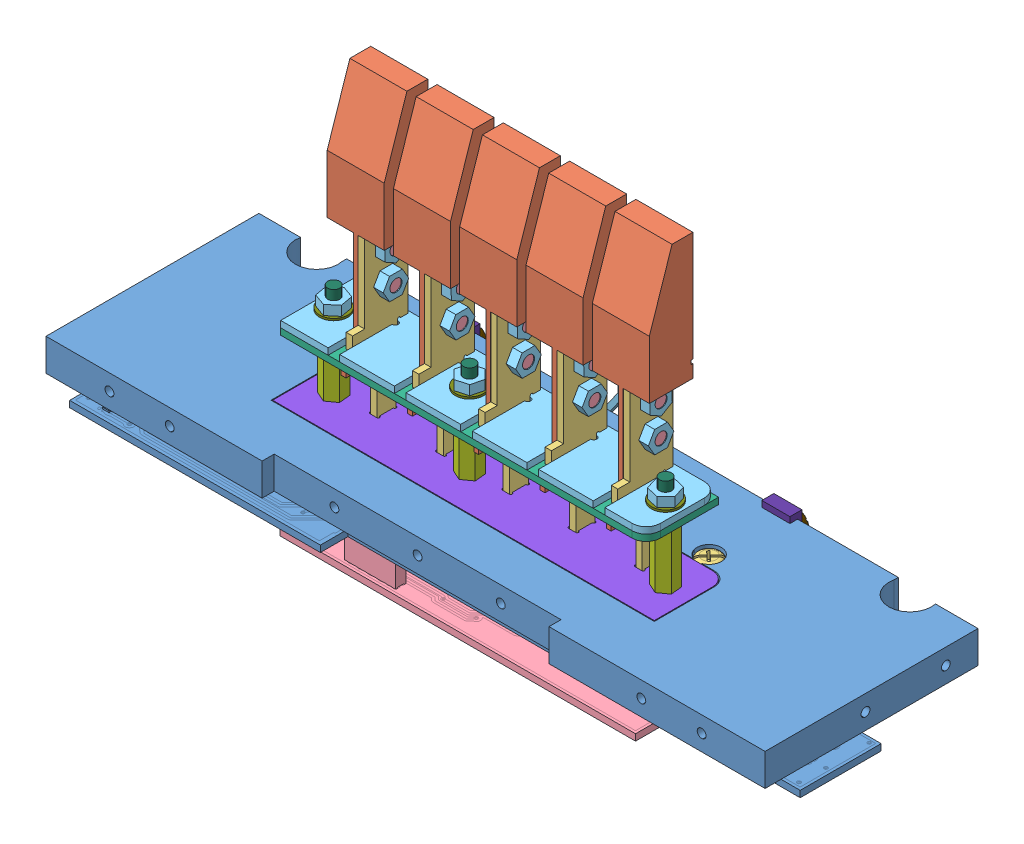
SolidWorks assembly 0200_ASM_Keyboard_PCB_stepmotor, configuration Default. Lengths in mm.
Overall size (179 155.71 164.54).
83 component instances, 24 part files, 108 mates.
Components (placement in the parent):
- 0201 Keyboard_PCB_holder-1: 0201 Keyboard_PCB_holder [Domyślna] at (-12.0126 94.407 53.9399) size (179 8 54.1)
- 0202 Button_ASM-1: 0202 Button_ASM [Domyślna] at (47.1081 156.1513 102.1514) x (0 1 0) z (1 0 0) size (82.15 13.85 14.2)
  - 0008 Button_Mustang_radio-1: 0008 Button_Mustang_radio [Domyślna] at (23.1329 -11.9839 53.65) size (60.75 13.85 14.2)
  - 0202_02 Button_pusher-1: 0202_02 Button_pusher [Domyślna] at (-73.7457 12.6375 84.3669) x (0 0 1) z (1 0 0) size (1.62 13.8 50.65)
  - 0301_03 M3_5 screw-1: 0301_03 M3_5 screw [Domyślna] at (-23.1095 5.1722 60.15) x (0.994507 -0.104669 0) z (0 0 -1) size (6 6 7.48)
  - 0301_03 M3_5 screw-2: 0301_03 M3_5 screw [Domyślna] at (-13.9404 2.6786 60.15) x (0.570039 -0.821618 0) z (0 0 -1) size (6 6 7.48)
  - 0301_02 M3 nut-1: 0301_02 M3 nut [Domyślna] at (-17.2457 2.6499 62.95) x (0.871112 -0.491084 0) z (0 0 1) size (5.51 6.35 2.4)
  - 0301_02 M3 nut-2: 0301_02 M3 nut [Domyślna] at (-25.2457 2.6499 62.95) size (5.51 6.35 2.4)
- 0202 Button_ASM-10: 0202 Button_ASM [Domyślna] at (63.6081 156.1513 102.1514) x (0 1 0) z (1 0 0) size (82.15 13.85 14.2)
  - 0008 Button_Mustang_radio-1: 0008 Button_Mustang_radio [Domyślna] at (23.1329 -11.9839 53.65) size (60.75 13.85 14.2)
  - 0202_02 Button_pusher-1: 0202_02 Button_pusher [Domyślna] at (-73.7457 12.6375 84.3669) x (0 0 1) z (1 0 0) size (1.62 13.8 50.65)
  - 0301_03 M3_5 screw-1: 0301_03 M3_5 screw [Domyślna] at (-23.1095 5.1722 60.15) x (0.994507 -0.104669 0) z (0 0 -1) size (6 6 7.48)
  - 0301_03 M3_5 screw-2: 0301_03 M3_5 screw [Domyślna] at (-13.9404 2.6786 60.15) x (0.570039 -0.821618 0) z (0 0 -1) size (6 6 7.48)
  - 0301_02 M3 nut-1: 0301_02 M3 nut [Domyślna] at (-17.2457 2.6499 62.95) x (0.871112 -0.491084 0) z (0 0 1) size (5.51 6.35 2.4)
  - 0301_02 M3 nut-2: 0301_02 M3 nut [Domyślna] at (-25.2457 2.6499 62.95) size (5.51 6.35 2.4)
- 0202 Button_ASM-11: 0202 Button_ASM [Domyślna] at (80.1081 156.1513 102.1514) x (0 1 0) z (1 0 0) size (82.15 13.85 14.2)
  - 0008 Button_Mustang_radio-1: 0008 Button_Mustang_radio [Domyślna] at (23.1329 -11.9839 53.65) size (60.75 13.85 14.2)
  - 0202_02 Button_pusher-1: 0202_02 Button_pusher [Domyślna] at (-73.7457 12.6375 84.3669) x (0 0 1) z (1 0 0) size (1.62 13.8 50.65)
  - 0301_03 M3_5 screw-1: 0301_03 M3_5 screw [Domyślna] at (-23.1095 5.1722 60.15) x (0.994507 -0.104669 0) z (0 0 -1) size (6 6 7.48)
  - 0301_03 M3_5 screw-2: 0301_03 M3_5 screw [Domyślna] at (-13.9404 2.6786 60.15) x (0.570039 -0.821618 0) z (0 0 -1) size (6 6 7.48)
  - 0301_02 M3 nut-1: 0301_02 M3 nut [Domyślna] at (-17.2457 2.6499 62.95) x (0.871112 -0.491084 0) z (0 0 1) size (5.51 6.35 2.4)
  - 0301_02 M3 nut-2: 0301_02 M3 nut [Domyślna] at (-25.2457 2.6499 62.95) size (5.51 6.35 2.4)
- 0202 Button_ASM-12: 0202 Button_ASM [Domyślna] at (30.6081 156.1513 102.1514) x (0 1 0) z (1 0 0) size (82.15 13.85 14.2)
  - 0008 Button_Mustang_radio-1: 0008 Button_Mustang_radio [Domyślna] at (23.1329 -11.9839 53.65) size (60.75 13.85 14.2)
  - 0202_02 Button_pusher-1: 0202_02 Button_pusher [Domyślna] at (-73.7457 12.6375 84.3669) x (0 0 1) z (1 0 0) size (1.62 13.8 50.65)
  - 0301_03 M3_5 screw-1: 0301_03 M3_5 screw [Domyślna] at (-23.1095 5.1722 60.15) x (0.994507 -0.104669 0) z (0 0 -1) size (6 6 7.48)
  - 0301_03 M3_5 screw-2: 0301_03 M3_5 screw [Domyślna] at (-13.9404 2.6786 60.15) x (0.570039 -0.821618 0) z (0 0 -1) size (6 6 7.48)
  - 0301_02 M3 nut-1: 0301_02 M3 nut [Domyślna] at (-17.2457 2.6499 62.95) x (0.871112 -0.491084 0) z (0 0 1) size (5.51 6.35 2.4)
  - 0301_02 M3 nut-2: 0301_02 M3 nut [Domyślna] at (-25.2457 2.6499 62.95) size (5.51 6.35 2.4)
- 0202 Button_ASM-13: 0202 Button_ASM [Domyślna] at (14.1081 156.1513 102.1514) x (0 1 0) z (1 0 0) size (82.15 13.85 14.2)
  - 0008 Button_Mustang_radio-1: 0008 Button_Mustang_radio [Domyślna] at (23.1329 -11.9839 53.65) size (60.75 13.85 14.2)
  - 0202_02 Button_pusher-1: 0202_02 Button_pusher [Domyślna] at (-73.7457 12.6375 84.3669) x (0 0 1) z (1 0 0) size (1.62 13.8 50.65)
  - 0301_03 M3_5 screw-1: 0301_03 M3_5 screw [Domyślna] at (-23.1095 5.1722 60.15) x (0.994507 -0.104669 0) z (0 0 -1) size (6 6 7.48)
  - 0301_03 M3_5 screw-2: 0301_03 M3_5 screw [Domyślna] at (-13.9404 2.6786 60.15) x (0.570039 -0.821618 0) z (0 0 -1) size (6 6 7.48)
  - 0301_02 M3 nut-1: 0301_02 M3 nut [Domyślna] at (-17.2457 2.6499 62.95) x (0.871112 -0.491084 0) z (0 0 1) size (5.51 6.35 2.4)
  - 0301_02 M3 nut-2: 0301_02 M3 nut [Domyślna] at (-25.2457 2.6499 62.95) size (5.51 6.35 2.4)
- 0203_02 Popychacz_plytka_przod_tyl-1: 0203_02 Popychacz_plytka_przod_tyl [Domyślna] at (92.8637 117.407 124.3828) x (1 0 0) z (0 1 0) size (91 18 1.6)
- 0302_01_15 AVT_M3_15 W_W-1: 0302_01_15 AVT_M3_15 W_W [Domyślna] at (66.5581 117.407 107.4012) x (1 0 0) z (0 -1 0) size (5.25 5.75 15)
- 0302_01_15 AVT_M3_15 W_W-2: 0302_01_15 AVT_M3_15 W_W [Domyślna] at (149.1581 117.407 107.4012) x (1 0 0) z (0 -1 0) size (5.25 5.75 15)
- 0204_01_02 Popychacz_plytka_tyl_obie-3: 0204_01_02 Popychacz_plytka_tyl_obie [Domyślna] at (109.6559 100.807 132.332) x (1 0 0) z (0 1 0) size (95 164.54 1.61)
- 0204_01_02 Popychacz_plytka_tyl_obie-5: 0204_01_02 Popychacz_plytka_tyl_obie [Domyślna] at (109.6559 94.407 132.332) x (1 0 0) z (0 1 0) size (95 164.54 1.61)
- 0303_01_20 AVT_ FIX-3.5-7-1: 0303_01_20 AVT_ FIX-3.5-7 [Domyślna] at (149.1581 94.407 107.4012) x (-0.241888 0 -0.970304) z (0 -1 0) size (6.3 6.3 7)
- 0303_01_20 AVT_ FIX-3.5-7-2: 0303_01_20 AVT_ FIX-3.5-7 [Domyślna] at (66.5581 94.407 107.4012) x (0.447853 0 0.894107) z (0 -1 0) size (6.3 6.3 7)
- 0204 18_degree_Stepper_motor_ASM-1: 0204 18_degree_Stepper_motor_ASM [Domyślna] at (84.148 89.7518 -20.7788) x (-1 0 0) z (0 0 1) size (123.94 152.42 25.76)
  - Podstawa-1: Podstawa [Domyślna] at (-23.4331 3.418 97.5) size (123.94 152.42 15.11)
  - PCB_złożenie_PART_ASM-1: PCB_złożenie_PART_ASM [Domyślna] at (30.2257 4.23 104.2) x (1 0 0) z (0 0 -1) size (19.02 7.5 10.76)
  - prowadnica-1: prowadnica [Domyślna] at (21.2899 4.3448 105) x (0 0 1) z (-1 0 0) size (3 3 90)
  - suwak-1: suwak [Domyślna] at (-12.9526 -22.7417 105.613) x (0 -1 0) z (-1 0 0) size (12.4 15 7.5)
  - prowadnica-2: prowadnica [Domyślna] at (-68.7101 0.0448 109.845) x (0 0 -1) z (1 0 0) size (3 3 90)
  - prowadnica-3: prowadnica [Domyślna] at (21.2899 0.0448 100.155) x (0 0 1) z (-1 0 0) size (3 3 90)
- 0004 HMI pointer-1: 0004 HMI pointer [Default] at (105.5919 80.157 79.2046) x (0 -1 0) z (0 0 1) size (54.01 6.75 30.62)
- 0301_05 M3_40 screw-1: 0301_05 M3_40 screw [Domyślna] at (151.1235 85.907 110.0589) x (-0.3299 0 0.944016) z (0 -1 0) size (6 6 42.48)
- 0301_01 M3 washer-2: 0301_01 M3 washer [Domyślna] at (149.1581 120.607 107.4012) size (7 0.5 7)
- 0301_02 M3 nut-2: 0301_02 M3 nut [Domyślna] at (149.1581 123.507 107.4012) x (0.957402 0 -0.288759) z (0 -1 0) size (5.51 6.35 2.4)
- 0301_01 M3 washer-3: 0301_01 M3 washer [Domyślna] at (66.5581 120.607 107.4012) size (7 0.5 7)
- 0301_02 M3 nut-3: 0301_02 M3 nut [Domyślna] at (66.5581 121.107 107.4012) x (0.343062 0 -0.939313) z (0 1 0) size (5.51 6.35 2.4)
- 0301_05 M3_40 screw-2: 0301_05 M3_40 screw [Domyślna] at (69.5558 85.907 108.794) x (0.162196 0 0.986759) z (0 -1 0) size (6 6 42.48)
- 0303_01_20 AVT_ FIX-3.5-7-3: 0303_01_20 AVT_ FIX-3.5-7 [Domyślna] at (100.3581 94.407 107.4012) x (-0.431925 0 0.90191) z (0 -1 0) size (6.3 6.3 7)
- 0301_05 M3_40 screw-3: 0301_05 M3_40 screw [Domyślna] at (103.5204 85.907 106.4392) x (0.779048 0 0.626964) z (0 -1 0) size (6 6 42.48)
- 0301_01 M3 washer-4: 0301_01 M3 washer [Domyślna] at (100.3581 120.607 107.4012) size (7 0.5 7)
- 0301_02 M3 nut-4: 0301_02 M3 nut [Domyślna] at (100.3581 123.507 107.4012) x (0.694406 0 -0.719583) z (0 -1 0) size (5.51 6.35 2.4)
- 0302_01_15 AVT_M3_15 W_W-3: 0302_01_15 AVT_M3_15 W_W [Domyślna] at (100.3581 117.407 107.4012) x (1 0 0) z (0 -1 0) size (5.25 5.75 15)
- 0202 Motor holder-METAL-2: 0202 Motor holder-METAL [Domyślna] at (146.9154 94.407 82.6208) x (0 0 1) z (0 1 0) size (22.72 7 9) (hidden)
- 0202 Motor holder-METAL-3: 0202 Motor holder-METAL [Domyślna] at (66.7554 94.407 82.6208) x (0 0 1) z (0 1 0) size (22.72 7 9) (hidden)
- 0202 Motor holder-PRINTED-1: 0202 Motor holder-PRINTED [Domyślna] at (66.7554 93.407 82.9279) x (0 0 1) z (0 1 0) size (23 7 10.6)
- 0202 Motor holder-PRINTED-2: 0202 Motor holder-PRINTED [Domyślna] at (146.9154 93.407 82.9279) x (0 0 1) z (0 1 0) size (23 7 10.6)
- 0301_02 M3 nut-5: 0301_02 M3 nut [Domyślna] at (147.9381 91.007 95.3212) x (1 0 0) z (0 1 0) size (5.51 6.35 2.4)
- 0301_02 M3 nut-6: 0301_02 M3 nut [Domyślna] at (67.7781 93.407 95.3212) x (0.884436 0 0.466662) z (0 -1 0) size (5.51 6.35 2.4)
- 0301_01 M3 washer-7: 0301_01 M3 washer [Domyślna] at (147.9381 98.407 75.7212) x (1 0 0) z (0 1 0) size (7 0.5 7)
- 0301_03 M3_10 screw-1: 0301_03 M3_10 screw [Domyślna] at (150.929 96.9997 75.2212) x (0.157411 -0.987533 0) z (0 0 -1) size (6 6 12.48)
- 0301_01 M3 washer-8: 0301_01 M3 washer [Domyślna] at (67.7781 98.407 75.7212) x (1 0 0) z (0 1 0) size (7 0.5 7)
- 0301_03 M3_10 screw-2: 0301_03 M3_10 screw [Domyślna] at (71.0607 98.795 75.2212) x (0.656002 -0.754759 0) z (0 0 -1) size (6 6 12.48)
- 04_Keyboard-1: 04_Keyboard [Domyślna] at (-38.7519 87.537 14.8212) x (1 0 0) z (0 1 0) size (175 31 14.44)
- 0303_01_20 AVT_ FIX-3.5-14-3: 0303_01_20 AVT_ FIX-3.5-14 [Domyślna] at (147.9381 77.007 95.3212) x (1 0 0) z (0 1 0) size (6.3 6.3 14)
- 0303_01_20 AVT_ FIX-3.5-14-4: 0303_01_20 AVT_ FIX-3.5-14 [Domyślna] at (67.7781 77.007 95.3212) x (0.987736 0 -0.156132) z (0 1 0) size (6.3 6.3 14)
- 0301_04 M3_30 screw-1: 0301_04 M3_30 screw [Domyślna] at (149.0646 99.807 98.4288) x (0.968896 0 0.24747) z (0 1 0) size (6 6 32.48)
- 0301_04 M3_30 screw-2: 0301_04 M3_30 screw [Domyślna] at (70.0661 99.807 92.9357) x (-0.206921 0 -0.978358) z (0 1 0) size (6 6 32.48)
- 0301_01 M3 washer-9: 0301_01 M3 washer [Domyślna] at (147.9381 74.877 95.3212) size (7 0.5 7)
- 0301_02 M3 nut-7: 0301_02 M3 nut [Domyślna] at (147.9381 72.477 95.3212) x (1 0 0) z (0 1 0) size (5.51 6.35 2.4)
- 0301_02 M3 nut-8: 0301_02 M3 nut [Domyślna] at (67.7781 72.477 95.3212) x (1 0 0) z (0 1 0) size (5.51 6.35 2.4)
- 0301_01 M3 washer-10: 0301_01 M3 washer [Domyślna] at (67.7781 74.877 95.3212) size (7 0.5 7)
- 05_01 HMI_driver_stepper_motor-1: 05_01 HMI_driver_stepper_motor [Domyślna] at (-38.7719 76.977 14.8412) x (1 0 0) z (0 1 0) size (88.53 43.87 18.6)
- 0203_01 Popychacz_plytka_przod_przod-2: 0203_01 Popychacz_plytka_przod_przod [Domyślna] at (92.8637 119.007 124.3828) x (1 0 0) z (0 1 0) size (106.59 18 1.6)
Mates (geometry in assembly coordinates):
- Równolegle1: parallel aligned: plane of 0202 Button_ASM-1/0008 Button_Mustang_radio-1 through (107.8581 179.2842 90.1675) normal (1 0 0); plane of assembly through (107.8581 0 0) normal (1 0 0)
- Równolegle2: parallel anti-aligned: plane of 0201 Keyboard_PCB_holder-1 through (-12.0126 102.407 53.9399) normal (0 1 0); plane of 0202 Button_ASM-1/0202_02 Button_pusher-1 through (100.7581 113.1555 90.1675) normal (0 -1 0)
- Wspólnie2: coincident aligned: plane of 0202 Button_ASM-1/0008 Button_Mustang_radio-1 through (107.8581 179.2842 90.1675) normal (1 0 0); plane of assembly through (107.8581 0 0) normal (1 0 0)
- Wspólnie3: coincident aligned: plane of 0202 Button_ASM-1/0008 Button_Mustang_radio-1 through (114.9581 142.4055 99.3812) normal (0 0 -1); plane of assembly through (0 0 99.3812) normal (0 0 -1)
- Odległość1: distance = 1 mm aligned: plane of 0203_02 Popychacz_plytka_przod_tyl-1 through (62.3581 119.007 98.4012) normal (0 0 -1); plane of 0202 Button_ASM-10/0202_02 Button_pusher-1 through (124.9581 142.4055 99.4012) normal (0 0 -1)
- Wspólnie7: coincident aligned: plane of 0203_02 Popychacz_plytka_przod_tyl-1 through (107.8581 117.407 124.3828) normal (1 0 0); plane of assembly through (107.8581 0 0) normal (1 0 0)
- Wspólnie8: coincident anti-aligned: plane of 0202 Button_ASM-13/0008 Button_Mustang_radio-1 through (75.4581 117.407 113.2312) normal (0 1 0); plane of 0203_02 Popychacz_plytka_przod_tyl-1 through (92.8637 117.407 124.3828) normal (0 -1 0)
- Odległość2: distance = 15 mm anti-aligned: plane of 0201 Keyboard_PCB_holder-1 through (-12.0126 102.407 53.9399) normal (0 1 0); plane of 0203_02 Popychacz_plytka_przod_tyl-1 through (92.8637 117.407 124.3828) normal (0 -1 0)
- Wspólnie14: coincident anti-aligned: plane of 0203_02 Popychacz_plytka_przod_tyl-1 through (92.8637 117.407 124.3828) normal (0 -1 0); plane of 0302_01_15 AVT_M3_15 W_W-1 through (66.5581 117.407 107.4012) normal (0 1 0)
- Wspólnie15: coincident anti-aligned: plane of 0203_02 Popychacz_plytka_przod_tyl-1 through (92.8637 117.407 124.3828) normal (0 -1 0); plane of 0302_01_15 AVT_M3_15 W_W-2 through (149.1581 117.407 107.4012) normal (0 1 0)
- Równolegle5: parallel anti-aligned: plane of 0201 Keyboard_PCB_holder-1 through (-12.0126 102.407 53.9399) normal (0 1 0); plane of 0204_01_02 Popychacz_plytka_tyl_obie-3 through (109.6559 100.807 132.332) normal (0 -1 0)
- Wspólnie22: coincident aligned: plane of 0201 Keyboard_PCB_holder-1 through (-12.0126 102.407 53.9399) normal (0 1 0); plane of 0204_01_02 Popychacz_plytka_tyl_obie-3 through (109.6559 102.407 132.332) normal (0 1 0)
- Równolegle7: parallel anti-aligned: plane of 0201 Keyboard_PCB_holder-1 through (-12.0126 102.407 53.9399) normal (0 1 0); plane of 0204_01_02 Popychacz_plytka_tyl_obie-5 through (109.6559 94.407 132.332) normal (0 -1 0)
- Wspólnie27: coincident aligned: plane of 0204_01_02 Popychacz_plytka_tyl_obie-3 through (107.8581 100.807 132.332) normal (1 0 0); plane of 0204_01_02 Popychacz_plytka_tyl_obie-5 through (107.8581 94.407 132.332) normal (1 0 0)
- Wspólnie28: coincident aligned: plane of 0204_01_02 Popychacz_plytka_tyl_obie-3 through (109.6559 100.807 107.4012) normal (0 0 -1); plane of 0204_01_02 Popychacz_plytka_tyl_obie-5 through (109.6559 94.407 107.4012) normal (0 0 -1)
- Wspólnie29: coincident aligned: plane of 0201 Keyboard_PCB_holder-1 through (-12.0126 94.407 53.9399) normal (0 -1 0); plane of 0204_01_02 Popychacz_plytka_tyl_obie-5 through (109.6559 94.407 132.332) normal (0 -1 0)
- Koncentryczne2: concentric anti-aligned: circle of 0204_01_02 Popychacz_plytka_tyl_obie-5; cylinder of 0303_01_20 AVT_ FIX-3.5-7-1 through (149.1581 87.407 107.4012) axis (0 1 0) radius 1.75
- Wspólnie30: coincident anti-aligned: plane of 0204_01_02 Popychacz_plytka_tyl_obie-5 through (109.6559 94.407 132.332) normal (0 -1 0); plane of 0303_01_20 AVT_ FIX-3.5-7-1 through (149.1581 94.407 107.4012) normal (0 1 0)
- Koncentryczne3: concentric anti-aligned: cylinder of 0204_01_02 Popychacz_plytka_tyl_obie-5 through (66.5581 90.1644 107.4012) axis (0 1 0) radius 1.5; circle of 0303_01_20 AVT_ FIX-3.5-7-2
- Wspólnie31: coincident aligned: plane of 0204_01_02 Popychacz_plytka_tyl_obie-5 through (109.6559 94.407 132.332) normal (0 -1 0); circle of 0303_01_20 AVT_ FIX-3.5-7-2
- Wspólnie34: coincident aligned: plane of 0201 Keyboard_PCB_holder-1 through (-12.0126 94.407 76.7212) normal (0 0 -1); plane of 0204 18_degree_Stepper_motor_ASM-1/Podstawa-1 through (153.3581 94.907 76.7212) normal (0 0 -1)
- Równolegle9: parallel anti-aligned: plane of 0201 Keyboard_PCB_holder-1 through (-12.0126 94.407 53.9399) normal (0 -1 0); plane of 0204 18_degree_Stepper_motor_ASM-1/Podstawa-1 through (153.3581 95.907 91.7212) normal (0 1 0)
- Wspólnie35: coincident aligned: plane of 0204_01_02 Popychacz_plytka_tyl_obie-5 through (107.8581 94.407 132.332) normal (1 0 0); plane of 0204 18_degree_Stepper_motor_ASM-1/Podstawa-1 through (107.8581 86.3338 76.7212) normal (1 0 0)
- Wspólnie36: coincident aligned: plane of 0201 Keyboard_PCB_holder-1 through (-12.0126 94.407 53.9399) normal (0 -1 0); plane of 0204 18_degree_Stepper_motor_ASM-1/Podstawa-1 through (151.8581 94.407 91.7212) normal (0 -1 0)
- Wspólnie37: coincident anti-aligned: plane of 0204 18_degree_Stepper_motor_ASM-1/suwak-1 through (104.6006 80.907 91.7212) normal (0 -1 0); plane of 0004 HMI pointer-1 through (105.5919 80.907 79.2046) normal (0 1 0)
- Wspólnie38: coincident anti-aligned: plane of 0204 18_degree_Stepper_motor_ASM-1/suwak-1 through (104.6006 80.907 76.7212) normal (0 0 -1); plane of 0004 HMI pointer-1 through (105.5919 80.157 76.7212) normal (0 0 1)
- Wspólnie39: coincident aligned: plane of 0204 18_degree_Stepper_motor_ASM-1/suwak-1 through (104.6006 112.4935 84.8342) normal (1 0 0); plane of 0004 HMI pointer-1 through (104.6006 80.907 75.9712) normal (1 0 0)
- Koncentryczne5: concentric aligned: circle of 0303_01_20 AVT_ FIX-3.5-7-1; cylinder of 0301_05 M3_40 screw-1 through (149.1581 125.907 107.4012) axis (0 -1 0) radius 1.5
- Odległość3: distance = 1.5 mm anti-aligned: plane of 0303_01_20 AVT_ FIX-3.5-7-1 through (149.1581 87.407 107.4012) normal (0 -1 0); plane of 0301_05 M3_40 screw-1 through (149.1581 85.907 107.4012) normal (0 1 0)
- Koncentryczne6: concentric anti-aligned: cylinder of 0301_05 M3_40 screw-1 through (149.1581 125.907 107.4012) axis (0 -1 0) radius 1.5; circle of 0301_01 M3 washer-2
- Koncentryczne7: concentric anti-aligned: cylinder of 0301_05 M3_40 screw-1 through (149.1581 125.907 107.4012) axis (0 -1 0) radius 1.5; cylinder of 0301_02 M3 nut-2 through (149.1581 121.107 107.4012) axis (0 1 0) radius 1.4964
- Wspólnie46: coincident anti-aligned: plane of 0301_01 M3 washer-2 through (149.1581 121.107 107.4012) normal (0 1 0); plane of 0301_02 M3 nut-2 through (149.1581 121.107 107.4012) normal (0 -1 0)
- Koncentryczne8: concentric anti-aligned: cylinder of 0303_01_20 AVT_ FIX-3.5-7-2 through (66.5581 87.407 107.4012) axis (0 1 0) radius 1.75; cylinder of 0301_05 M3_40 screw-2 through (66.5581 125.907 107.4012) axis (0 -1 0) radius 1.5
- Odległość4: distance = 1.5 mm anti-aligned: plane of 0303_01_20 AVT_ FIX-3.5-7-2 through (66.5581 87.407 107.4012) normal (0 -1 0); plane of 0301_05 M3_40 screw-2 through (66.5581 85.907 107.4012) normal (0 1 0)
- Koncentryczne9: concentric anti-aligned: circle of 0301_01 M3 washer-3; cylinder of 0301_05 M3_40 screw-2 through (66.5581 125.907 107.4012) axis (0 -1 0) radius 1.5
- Koncentryczne10: concentric anti-aligned: circle of 0301_02 M3 nut-3; cylinder of 0301_05 M3_40 screw-2 through (66.5581 125.907 107.4012) axis (0 -1 0) radius 1.5
- Wspólnie49: coincident anti-aligned: circle of 0301_01 M3 washer-3; plane of 0301_02 M3 nut-3 through (66.5581 121.107 107.4012) normal (0 -1 0)
- Koncentryczne12: concentric anti-aligned: circle of 0204_01_02 Popychacz_plytka_tyl_obie-5; cylinder of 0303_01_20 AVT_ FIX-3.5-7-3 through (100.3581 87.407 107.4012) axis (0 1 0) radius 1.75
- Wspólnie50: coincident anti-aligned: plane of 0204_01_02 Popychacz_plytka_tyl_obie-5 through (109.6559 94.407 132.332) normal (0 -1 0); plane of 0303_01_20 AVT_ FIX-3.5-7-3 through (100.3581 94.407 107.4012) normal (0 1 0)
- Koncentryczne14: concentric anti-aligned: cylinder of 0303_01_20 AVT_ FIX-3.5-7-3 through (100.3581 87.407 107.4012) axis (0 1 0) radius 1.75; cylinder of 0301_05 M3_40 screw-3 through (100.3581 125.907 107.4012) axis (0 -1 0) radius 1.5
- Odległość6: distance = 1.5 mm anti-aligned: plane of 0303_01_20 AVT_ FIX-3.5-7-3 through (100.3581 87.407 107.4012) normal (0 -1 0); plane of 0301_05 M3_40 screw-3 through (100.3581 85.907 107.4012) normal (0 1 0)
- Koncentryczne15: concentric aligned: cylinder of 0301_05 M3_40 screw-3 through (100.3581 125.907 107.4012) axis (0 -1 0) radius 1.5; cylinder of 0301_01 M3 washer-4 through (100.3581 121.107 107.4012) axis (0 -1 0) radius 1.6
- Koncentryczne16: concentric anti-aligned: cylinder of 0301_05 M3_40 screw-3 through (100.3581 125.907 107.4012) axis (0 -1 0) radius 1.5; cylinder of 0301_02 M3 nut-4 through (100.3581 121.107 107.4012) axis (0 1 0) radius 1.4964
- Wspólnie54: coincident anti-aligned: plane of 0301_01 M3 washer-4 through (100.3581 121.107 107.4012) normal (0 1 0); plane of 0301_02 M3 nut-4 through (100.3581 121.107 107.4012) normal (0 -1 0)
- Koncentryczne17: concentric anti-aligned: cylinder of 0301_05 M3_40 screw-3 through (100.3581 125.907 107.4012) axis (0 -1 0) radius 1.5; cylinder of 0302_01_15 AVT_M3_15 W_W-3 through (100.3581 102.407 107.4012) axis (0 1 0) radius 1.5
- Wspólnie55: coincident anti-aligned: plane of 0204_01_02 Popychacz_plytka_tyl_obie-3 through (109.6559 102.407 132.332) normal (0 1 0); plane of 0302_01_15 AVT_M3_15 W_W-3 through (100.3581 102.407 107.4012) normal (0 -1 0)
- Wspólnie56: coincident anti-aligned: plane of 0201 Keyboard_PCB_holder-1 through (-12.0126 94.407 53.9399) normal (0 -1 0); plane of 0202 Motor holder-METAL-2 through (147.9381 94.407 95.3212) normal (0 1 0)
- Równolegle10: parallel aligned: plane of 0204 18_degree_Stepper_motor_ASM-1/Podstawa-1 through (154.3581 80.907 91.7212) normal (1 0 0); plane of 0202 Motor holder-METAL-2 through (151.4381 93.407 98.4367) normal (1 0 0)
- Wspólnie59: coincident anti-aligned: plane of 0201 Keyboard_PCB_holder-1 through (-12.0126 94.407 53.9399) normal (0 -1 0); plane of 0202 Motor holder-METAL-3 through (67.7781 94.407 95.3212) normal (0 1 0)
- Równolegle11: parallel aligned: plane of 0204 18_degree_Stepper_motor_ASM-1/Podstawa-1 through (152.8581 80.907 91.7212) normal (-1 0 0); plane of 0202 Motor holder-METAL-3 through (64.2781 93.407 76.7212) normal (-1 0 0)
- Wspólnie66: coincident anti-aligned: plane of 0202 Motor holder-METAL-2 through (146.9154 94.407 75.7212) normal (0 0 -1); plane of 0301_01 M3 washer-7 through (147.9381 98.407 75.7212) normal (0 0 1)
- Wspólnie67: coincident aligned: cylinder of 0202 Motor holder-METAL-2 through (147.9381 98.407 83.171) axis (0 0 -1) radius 1.6; circle of 0301_01 M3 washer-7
- Wspólnie68: coincident anti-aligned: plane of 0301_01 M3 washer-7 through (147.9381 98.407 75.2212) normal (0 0 -1); plane of 0301_03 M3_10 screw-1 through (147.9381 98.407 75.2212) normal (0 0 1)
- Koncentryczne28: concentric aligned: circle of 0301_01 M3 washer-7; cylinder of 0301_03 M3_10 screw-1 through (147.9381 98.407 85.2212) axis (0 0 -1) radius 1.5
- Wspólnie69: coincident anti-aligned: plane of 0202 Motor holder-METAL-3 through (66.7554 94.407 75.7212) normal (0 0 -1); plane of 0301_01 M3 washer-8 through (67.7781 98.407 75.7212) normal (0 0 1)
- Wspólnie71: coincident aligned: circle of 0202 Motor holder-METAL-3; circle of 0301_01 M3 washer-8
- Wspólnie72: coincident anti-aligned: plane of 0301_01 M3 washer-8 through (67.7781 98.407 75.2212) normal (0 0 -1); plane of 0301_03 M3_10 screw-2 through (67.7781 98.407 75.2212) normal (0 0 1)
- Koncentryczne29: concentric aligned: circle of 0301_01 M3 washer-8; cylinder of 0301_03 M3_10 screw-2 through (67.7781 98.407 85.2212) axis (0 0 -1) radius 1.5
- Wspólnie77: coincident: plane of 0201 Keyboard_PCB_holder-1 through (-12.0126 94.407 76.7212) normal (0 0 -1); line of 0202 Motor holder-METAL-2 through (144.4381 94.907 76.7212) axis (0 1 0)
- Wspólnie78: coincident: plane of 0201 Keyboard_PCB_holder-1 through (-12.0126 94.407 76.7212) normal (0 0 -1); line of 0202 Motor holder-METAL-3 through (71.2781 102.407 76.7212) axis (0 -1 0)
- Koncentryczne35: concentric anti-aligned: cylinder of 0201 Keyboard_PCB_holder-1 through (147.9381 106.6496 95.3212) axis (0 -1 0) radius 1.5; cylinder of 0202 Motor holder-METAL-2 through (147.9381 93.407 95.3212) axis (0 1 0) radius 1.6
- Koncentryczne36: concentric anti-aligned: cylinder of 0201 Keyboard_PCB_holder-1 through (67.7781 106.6496 95.3212) axis (0 -1 0) radius 1.5; cylinder of 0202 Motor holder-METAL-3 through (67.7781 93.407 95.3212) axis (0 1 0) radius 1.6
- Koncentryczne44: concentric aligned: cylinder of 0201 Keyboard_PCB_holder-1 through (147.9381 106.6496 95.3212) axis (0 -1 0) radius 1.5; cylinder of 0301_02 M3 nut-5 through (147.9381 93.407 95.3212) axis (0 -1 0) radius 1.4964
- Wspólnie84: coincident anti-aligned: plane of 0202 Motor holder-METAL-2 through (147.9381 93.407 95.3212) normal (0 -1 0); plane of 0301_02 M3 nut-5 through (147.9381 93.407 95.3212) normal (0 1 0)
- Koncentryczne45: concentric anti-aligned: cylinder of 0201 Keyboard_PCB_holder-1 through (67.7781 106.6496 95.3212) axis (0 -1 0) radius 1.5; cylinder of 0301_02 M3 nut-6 through (67.7781 91.007 95.3212) axis (0 1 0) radius 1.4964
- Wspólnie85: coincident anti-aligned: plane of 0202 Motor holder-METAL-3 through (67.7781 93.407 95.3212) normal (0 -1 0); plane of 0301_02 M3 nut-6 through (67.7781 93.407 95.3212) normal (0 1 0)
- Koncentryczne51: concentric anti-aligned: circle of 0301_02 M3 nut-6; circle of 0303_01_20 AVT_ FIX-3.5-14-4
- Wspólnie88: coincident anti-aligned: plane of 0301_02 M3 nut-6 through (67.7781 91.007 95.3212) normal (0 -1 0); plane of 0303_01_20 AVT_ FIX-3.5-14-4 through (67.7781 91.007 95.3212) normal (0 1 0)
- Koncentryczne52: concentric anti-aligned: circle of 0301_02 M3 nut-5; cylinder of 0303_01_20 AVT_ FIX-3.5-14-3 through (147.9381 91.007 95.3212) axis (0 -1 0) radius 1.75
- Wspólnie89: coincident anti-aligned: plane of 0301_02 M3 nut-5 through (147.9381 91.007 95.3212) normal (0 -1 0); circle of 0303_01_20 AVT_ FIX-3.5-14-3
- Koncentryczne55: concentric anti-aligned: cylinder of 0201 Keyboard_PCB_holder-1 through (147.9381 106.6496 95.3212) axis (0 -1 0) radius 1.5; cylinder of 0301_04 M3_30 screw-1 through (147.9381 69.807 95.3212) axis (0 1 0) radius 1.5
- Wspólnie90: coincident anti-aligned: plane of 0201 Keyboard_PCB_holder-1 through (147.9381 99.807 95.3212) normal (0 1 0); plane of 0301_04 M3_30 screw-1 through (147.9381 99.807 95.3212) normal (0 -1 0)
- Koncentryczne56: concentric anti-aligned: cylinder of 0201 Keyboard_PCB_holder-1 through (67.7781 106.6496 95.3212) axis (0 -1 0) radius 1.5; cylinder of 0301_04 M3_30 screw-2 through (67.7781 69.807 95.3212) axis (0 1 0) radius 1.5
- Wspólnie91: coincident anti-aligned: plane of 0201 Keyboard_PCB_holder-1 through (67.7781 99.807 95.3212) normal (0 1 0); plane of 0301_04 M3_30 screw-2 through (67.7781 99.807 95.3212) normal (0 -1 0)
- Koncentryczne58: concentric anti-aligned: circle of 0301_01 M3 washer-9; cylinder of 0301_02 M3 nut-7 through (147.9381 74.877 95.3212) axis (0 -1 0) radius 1.4964
- Wspólnie93: coincident anti-aligned: plane of 0301_01 M3 washer-9 through (147.9381 74.877 95.3212) normal (0 -1 0); plane of 0301_02 M3 nut-7 through (147.9381 74.877 95.3212) normal (0 1 0)
- Koncentryczne60: concentric anti-aligned: cylinder of 0301_02 M3 nut-8 through (67.7781 74.877 95.3212) axis (0 -1 0) radius 1.4964; circle of 0301_01 M3 washer-10
- Wspólnie95: coincident anti-aligned: plane of 0301_02 M3 nut-8 through (67.7781 74.877 95.3212) normal (0 1 0); plane of 0301_01 M3 washer-10 through (67.7781 74.877 95.3212) normal (0 -1 0)
- Koncentryczne61: concentric anti-aligned: cylinder of 0303_01_20 AVT_ FIX-3.5-7-1 through (149.1581 87.407 107.4012) axis (0 1 0) radius 3.15; cylinder of 0301_05 M3_40 screw-1 through (149.1581 125.907 107.4012) axis (0 -1 0) radius 1.5
- Wspólnie96: coincident aligned: plane of 0204_01_02 Popychacz_plytka_tyl_obie-5 through (109.6559 94.407 132.332) normal (0 -1 0); circle of 0303_01_20 AVT_ FIX-3.5-7-1
- Koncentryczne62: concentric anti-aligned: cylinder of 0303_01_20 AVT_ FIX-3.5-7-3 through (100.3581 87.407 107.4012) axis (0 1 0) radius 3.15; cylinder of 0301_05 M3_40 screw-3 through (100.3581 125.907 107.4012) axis (0 -1 0) radius 1.5
- Wspólnie97: coincident aligned: plane of 0204_01_02 Popychacz_plytka_tyl_obie-5 through (109.6559 94.407 132.332) normal (0 -1 0); circle of 0303_01_20 AVT_ FIX-3.5-7-3
- Koncentryczne63: concentric anti-aligned: cylinder of 0303_01_20 AVT_ FIX-3.5-7-2 through (66.5581 87.407 107.4012) axis (0 1 0) radius 3.15; cylinder of 0301_05 M3_40 screw-2 through (66.5581 125.907 107.4012) axis (0 -1 0) radius 1.5
- Wspólnie98: coincident aligned: plane of 0204_01_02 Popychacz_plytka_tyl_obie-5 through (109.6559 94.407 132.332) normal (0 -1 0); circle of 0303_01_20 AVT_ FIX-3.5-7-2
- Koncentryczne64: concentric anti-aligned: cylinder of 0301_05 M3_40 screw-2 through (66.5581 125.907 107.4012) axis (0 -1 0) radius 1.5; cylinder of 04_Keyboard-1 through (66.5581 87.537 107.4012) axis (0 1 0) radius 1.5
- Koncentryczne65: concentric aligned: circle of 0301_05 M3_40 screw-1; circle of 04_Keyboard-1
- Wspólnie99: coincident anti-aligned: circle of 0301_05 M3_40 screw-2; plane of 04_Keyboard-1 through (32.8761 85.907 124.5492) normal (0 1 0)
- Równolegle12: parallel anti-aligned: plane of 0201 Keyboard_PCB_holder-1 through (-12.0126 94.407 53.9399) normal (0 -1 0); plane of 05_01 HMI_driver_stepper_motor-1 through (107.2781 77.007 112.6312) normal (0 1 0)
- Wspólnie101: coincident anti-aligned: plane of 04_Keyboard-1 through (79.2921 88.937 115.4712) normal (-1 0 0); plane of 05_01 HMI_driver_stepper_motor-1 through (79.2921 83.677 114.8712) normal (1 0 0)
- Wspólnie102: coincident anti-aligned: plane of 04_Keyboard-1 through (79.2921 88.937 115.4712) normal (0 0 1); plane of 05_01 HMI_driver_stepper_motor-1 through (79.2921 83.677 115.4712) normal (0 0 -1)
- Wspólnie103: coincident anti-aligned: plane of 0303_01_20 AVT_ FIX-3.5-14-4 through (67.7781 77.007 95.3212) normal (0 -1 0); plane of 05_01 HMI_driver_stepper_motor-1 through (107.2781 77.007 112.6312) normal (0 1 0)
- Wspólnie104: coincident anti-aligned: plane of 0203_02 Popychacz_plytka_przod_tyl-1 through (92.8637 119.007 124.3828) normal (0 1 0); plane of 0203_01 Popychacz_plytka_przod_przod-2 through (92.8637 119.007 124.3828) normal (0 -1 0)
- Koncentryczne66: concentric anti-aligned: cylinder of 0201 Keyboard_PCB_holder-1 through (100.3581 91.7644 107.4012) axis (0 1 0) radius 1.5; cylinder of 0301_05 M3_40 screw-3 through (100.3581 125.907 107.4012) axis (0 -1 0) radius 1.5
- Wspólnie107: coincident anti-aligned: plane of 0301_01 M3 washer-4 through (100.3581 120.607 107.4012) normal (0 -1 0); plane of 0203_01 Popychacz_plytka_przod_przod-2 through (92.8637 120.607 124.3828) normal (0 1 0)
- Koncentryczne67: concentric aligned: cylinder of 0203_02 Popychacz_plytka_przod_tyl-1 through (66.5581 113.1644 107.4012) axis (0 1 0) radius 1.5; cylinder of 0203_01 Popychacz_plytka_przod_przod-2 through (66.5581 114.7644 107.4012) axis (0 1 0) radius 1.5
- Koncentryczne68: concentric aligned: cylinder of 0203_02 Popychacz_plytka_przod_tyl-1 through (149.1581 113.1644 107.4012) axis (0 1 0) radius 1.5; cylinder of 0203_01 Popychacz_plytka_przod_przod-2 through (149.1581 114.7644 107.4012) axis (0 1 0) radius 1.5
- Wspólnie110: coincident aligned: circle of 0301_01 M3 washer-2; plane of 0203_01 Popychacz_plytka_przod_przod-2 through (92.8637 120.607 124.3828) normal (0 1 0)
- Wspólnie111: coincident anti-aligned: plane of 0301_01 M3 washer-3 through (66.5581 120.607 107.4012) normal (0 -1 0); plane of 0203_01 Popychacz_plytka_przod_przod-2 through (92.8637 120.607 124.3828) normal (0 1 0)
- Koncentryczne69: concentric anti-aligned: cylinder of 0302_01_15 AVT_M3_15 W_W-1 through (66.5581 102.407 107.4012) axis (0 1 0) radius 1.5; cylinder of 0301_05 M3_40 screw-2 through (66.5581 125.907 107.4012) axis (0 -1 0) radius 1.5
- Wspólnie113: coincident aligned: circle of 0302_01_15 AVT_M3_15 W_W-2; cylinder of 0301_05 M3_40 screw-1 through (149.1581 125.907 107.4012) axis (0 -1 0) radius 1.5
- Wspólnie114: coincident aligned: plane of 0203_02 Popychacz_plytka_przod_tyl-1 through (62.3581 119.007 98.4012) normal (-1 0 0); plane of 0203_01 Popychacz_plytka_przod_przod-2 through (62.3581 120.607 98.4012) normal (-1 0 0)
- Wspólnie115: coincident aligned: plane of 0203_02 Popychacz_plytka_przod_tyl-1 through (62.3581 119.007 98.4012) normal (0 0 -1); plane of 0203_01 Popychacz_plytka_przod_przod-2 through (62.3581 120.607 98.4012) normal (0 0 -1)
- Wspólnie117: coincident aligned: plane of 0202 Motor holder-METAL-3 through (67.7781 93.407 95.3212) normal (0 -1 0); plane of 0202 Motor holder-PRINTED-1 through (67.7781 93.407 95.6283) normal (0 -1 0)
- Wspólnie118: coincident aligned: plane of 0202 Motor holder-METAL-3 through (66.7554 94.407 75.7212) normal (0 0 -1); plane of 0202 Motor holder-PRINTED-1 through (71.2781 94.407 75.7212) normal (0 0 -1)
- Wspólnie119: coincident aligned: plane of 0202 Motor holder-METAL-3 through (64.2781 102.407 75.7212) normal (-1 0 0); plane of 0202 Motor holder-PRINTED-1 through (64.2781 94.407 75.7212) normal (-1 0 0)
- Wspólnie120: coincident aligned: plane of 0202 Motor holder-METAL-2 through (147.9381 93.407 95.3212) normal (0 -1 0); plane of 0202 Motor holder-PRINTED-2 through (147.9381 93.407 95.6283) normal (0 -1 0)
- Wspólnie121: coincident aligned: plane of 0202 Motor holder-METAL-2 through (146.9154 94.407 75.7212) normal (0 0 -1); plane of 0202 Motor holder-PRINTED-2 through (151.4381 94.407 75.7212) normal (0 0 -1)
- Wspólnie122: coincident aligned: plane of 0202 Motor holder-METAL-2 through (151.4381 94.407 75.7212) normal (1 0 0); plane of 0202 Motor holder-PRINTED-2 through (151.4381 94.407 98.7212) normal (1 0 0)
